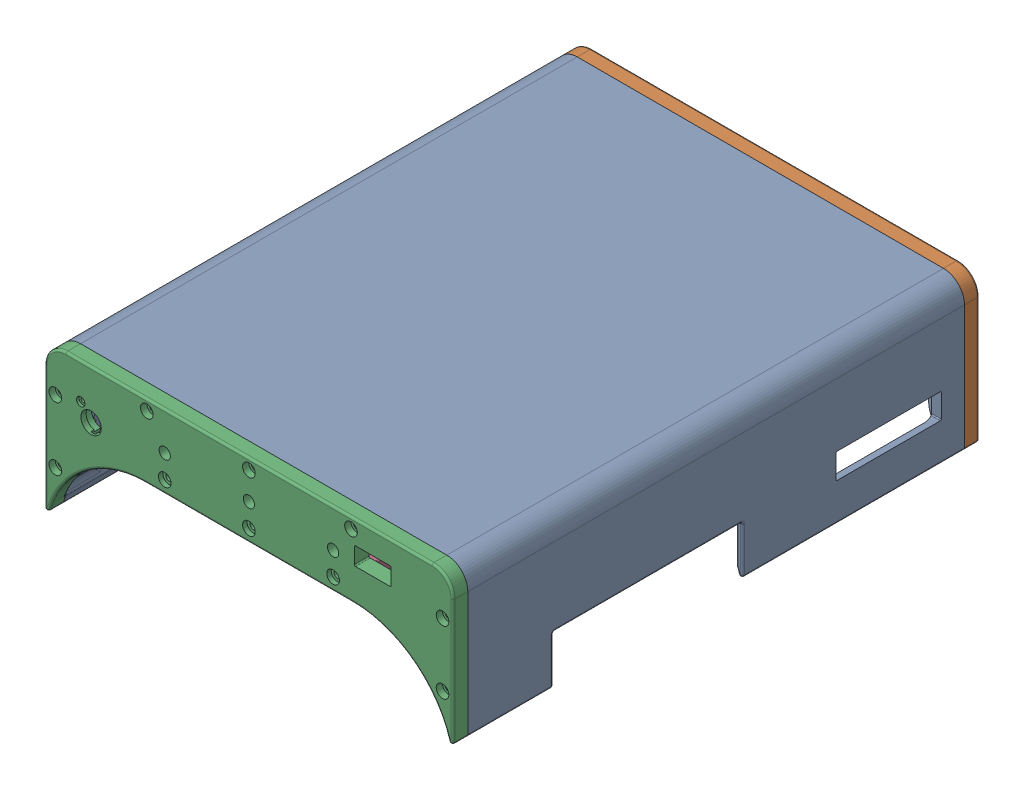
SolidWorks assembly macmini_shell_compact_full-back, configuration Default. Lengths in mm.
Overall size (194 69.79 250).
5 component instances, 4 part files, 12 mates.
Components (placement in the parent):
- shell_main-1: shell_main [Default] at (75.6607 24.5678 97.483) size (194 69.79 236)
- shell_back-1: shell_back [Default] at (75.6607 24.5678 97.483) size (194 69.79 37)
- shell_front-1: shell_front [Default] at (75.6607 24.5678 97.483) size (194 69.79 9)
- shell_robot_connector-1: shell_robot_connector [Default] at (75.6607 81.5678 206.783) size (100 12.8 12.7)
- shell_robot_connector-2: shell_robot_connector [Default] at (75.6607 81.5678 -11.817) x (-1 0 0) z (0 0 -1) size (100 12.8 12.7)
Mates (geometry in assembly coordinates):
- Concentric1: concentric anti-aligned: circle of back_shell_V3-1; circle of back_shell_P1_V3-1
- Concentric2: concentric anti-aligned: circle of back_shell_V3-1; circle of back_shell_P1_V3-1
- Coincident1: coincident anti-aligned: plane of back_shell_V3-1 through (75.6607 24.5678 -20.517) normal (0 0 -1); plane of back_shell_P1_V3-1 through (124.6607 33.5678 -20.517) normal (0 0 1)
- Concentric3: concentric anti-aligned: circle of back_shell_V3-1; circle of back_shell_P2-1
- Concentric4: concentric anti-aligned: circle of back_shell_V3-1; circle of back_shell_P2-1
- Coincident2: coincident anti-aligned: plane of back_shell_V3-1 through (75.6607 24.5678 215.483) normal (0 0 1); plane of back_shell_P2-1 through (124.6607 33.5678 215.483) normal (0 0 -1)
- Coincident4: coincident anti-aligned: plane of shell_front-1 through (124.6607 33.5678 215.483) normal (0 0 -1); plane of shell_robot_connector-1 through (25.6607 93.5678 215.483) normal (0 0 1)
- Concentric7: concentric aligned: cylinder of shell_front-1 through (35.6607 87.5678 202.483) axis (0 0 1) radius 1.6; cylinder of shell_robot_connector-1 through (35.6607 87.5678 165.483) axis (0 0 1) radius 1.6
- Concentric8: concentric aligned: cylinder of shell_front-1 through (115.6607 87.5678 202.483) axis (0 0 1) radius 1.6; cylinder of shell_robot_connector-1 through (115.6607 87.5678 165.483) axis (0 0 1) radius 1.6
- Coincident5: coincident anti-aligned: plane of shell_back-1 through (124.6607 33.5678 -20.517) normal (0 0 1); plane of shell_robot_connector-2 through (125.6607 93.5678 -20.517) normal (0 0 -1)
- Concentric9: concentric aligned: cylinder of shell_back-1 through (115.6607 87.5678 -7.517) axis (0 0 -1) radius 1.6; cylinder of shell_robot_connector-2 through (115.6607 87.5678 29.483) axis (0 0 -1) radius 1.6
- Concentric10: concentric aligned: cylinder of shell_back-1 through (35.6607 87.5678 -7.517) axis (0 0 -1) radius 1.6; cylinder of shell_robot_connector-2 through (35.6607 87.5678 29.483) axis (0 0 -1) radius 1.6
